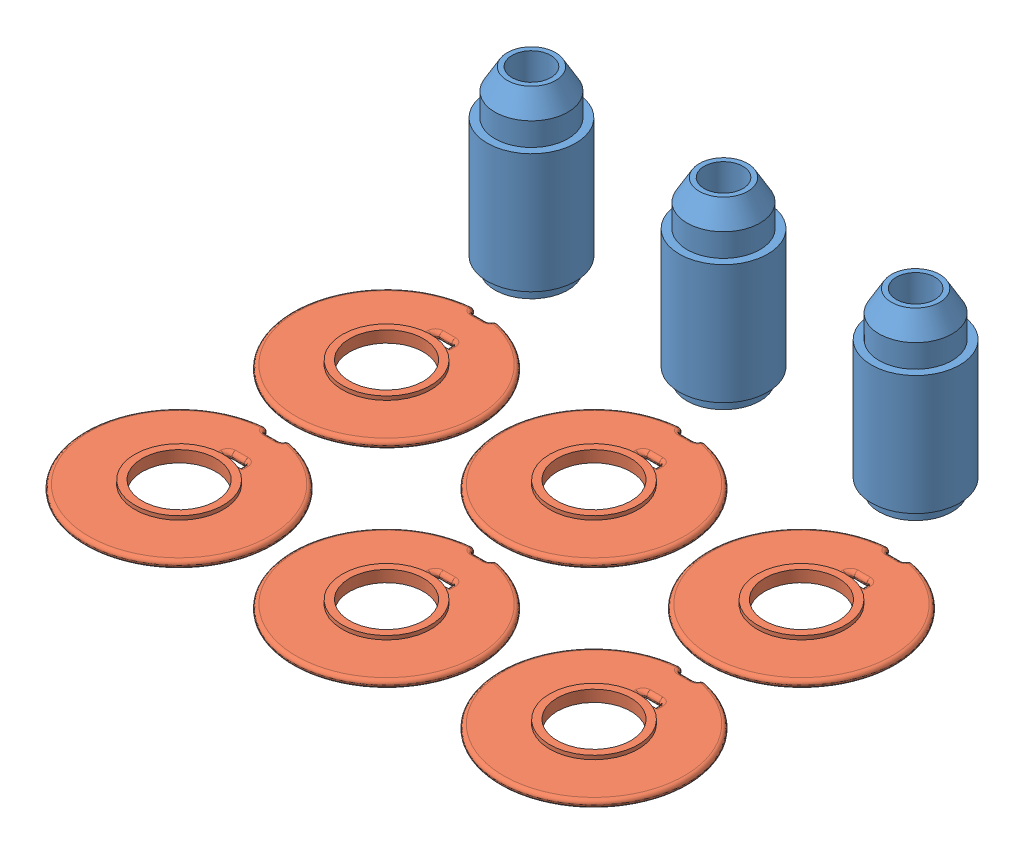
SolidWorks assembly bobbin_print, configuration Default. Lengths in mm.
Overall size (157 45.66 132.34).
9 component instances, 2 part files, 1 mates.
Components (placement in the parent):
- source_core-2: source_core [Default] at (-4.6231 17.56 -96.3389) x (-1 0 0) z (0 0 1) size (23 45.66 23)
- cheek-1: cheek [Default] at origin size (49 3 48.9)
- cheek-4: cheek [Default] at (0 0 -54) size (49 3 48.9)
- cheek-6: cheek [Default] at (54 0 0) size (49 3 48.9)
- cheek-7: cheek [Default] at (54 0 -54) size (49 3 48.9)
- cheek-9: cheek [Default] at (108 0 0) size (49 3 48.9)
- cheek-10: cheek [Default] at (108 0 -54) size (49 3 48.9)
- source_core-3: source_core [Default] at (45.3769 17.56 -96.3389) x (-1 0 0) z (0 0 1) size (23 45.66 23)
- source_core-4: source_core [Default] at (95.3769 17.56 -96.3389) x (-1 0 0) z (0 0 1) size (23 45.66 23)
Mates (geometry in assembly coordinates):
- Coincident3: coincident: plane of source_core-2 through (-9.6731 -1 -96.3389) normal (0 -1 0); plane of cheek-1 through (9.6 -1 0) normal (0 -1 0)
